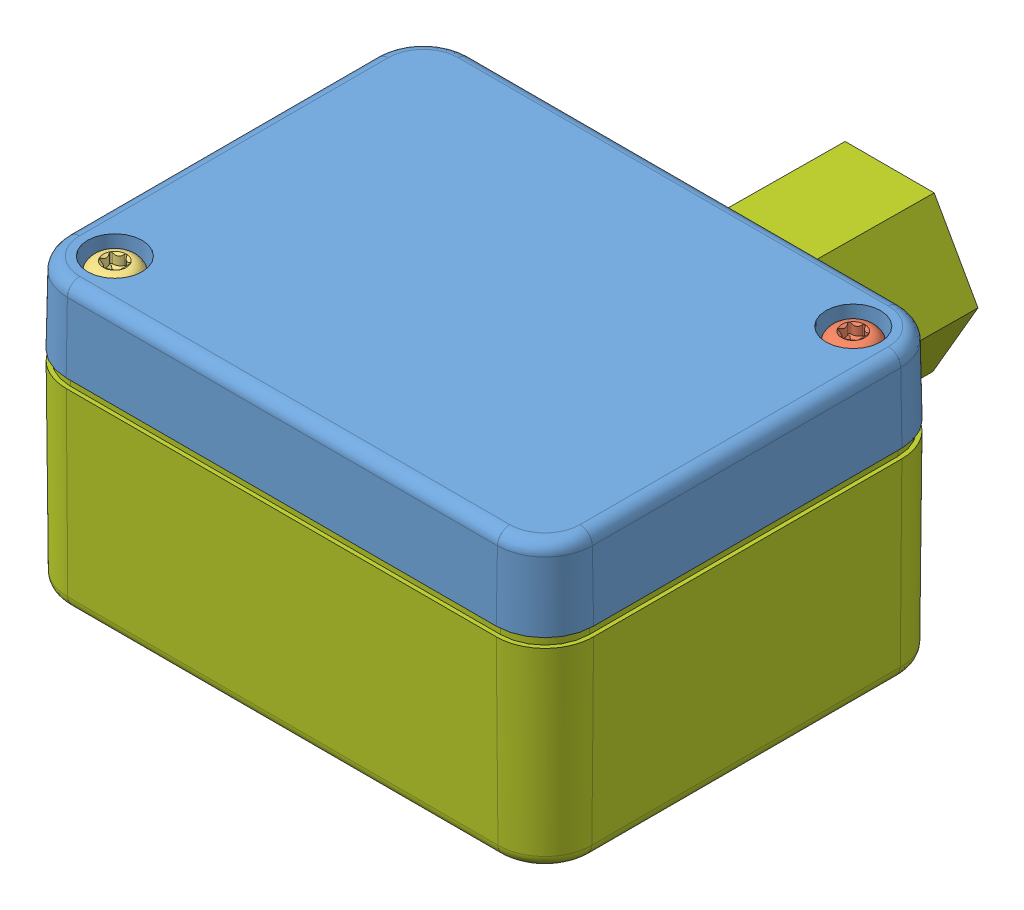
SolidWorks assembly serpac_camera_enclosure, configuration Default. Lengths in mm.
Overall size (65.66 34.99 75.31).
9 component instances, 9 part files, 3 mates.
Components (placement in the parent):
- RB32-X04Y REV C(Default)-1: RB32-X04Y REV C(Default) [Default] at origin size (65 10 50)
- 6023_Pan_Head_screw_torx_head-4-40_Rev_B-1: 6023_Pan_Head_screw_torx_head-4-40_Rev_B [Default] at (26.4999 -17.94 -19) x (1 0 0) z (0 1 0) size (5.56 5.56 27.69)
- 6023_Pan_Head_screw_torx_head-4-40_Rev_B-1-1: 6023_Pan_Head_screw_torx_head-4-40_Rev_B-1 [Default] at (-26.4999 -17.94 19) x (1 0 0) z (0 1 0) size (5.56 5.56 27.69)
- 6102_4-40_threaded insert-1: 6102_4-40_threaded insert [Default] at (26.4999 -6.096 -19) x (-0.837169 0 -0.546944) z (-0.546944 0 0.837169) size (5.82 5.08 5.82)
- 6102_4-40_threaded insert-1-1: 6102_4-40_threaded insert-1 [Default] at (-26.4999 -6.096 19) x (-0.837169 0 -0.546944) z (-0.546944 0 0.837169) size (5.82 5.08 5.82)
- 6022 #10-16 HL Pan HD-1: 6022 #10-16 HL Pan HD [Default] at (-18.9992 -17.018 0) x (1 0 0) z (0 1 0) size (8.18 8.18 9.67) (hidden)
- 6022 #10-16 HL Pan HD-1-1: 6022 #10-16 HL Pan HD-1 [Default] at (18.9992 -17.018 0) x (1 0 0) z (0 1 0) size (8.18 8.18 9.67) (hidden)
- 8032 RB32 O ring Rev A-1: 8032 RB32 O ring Rev A [Default] at origin size (62.56 2.03 47.57)
- Part12-1: Part12 [With Gland] x (-1 0 0) z (0 0 1) size (65.66 26.99 75.31)
Mates (geometry in assembly coordinates):
- Coincident1: coincident: plane of RB32-X04Y REV C(Default)-1 through (-26.4999 0 -19) normal (0 -1 0); plane of Part12-1 through (26.4999 0 -19) normal (0 1 0)
- Concentric1: concentric: cone of RB32-X04Y REV C(Default)-1 through (26.4999 5.969 -19) axis (0 1 0); cone of Part12-1 through (26.4999 0 -19) axis (0 1 0)
- Concentric2: concentric aligned: cone of RB32-X04Y REV C(Default)-1 through (-26.4999 5.969 19) axis (0 1 0); cone of Part12-1 through (-26.4999 0 19) axis (0 1 0)
